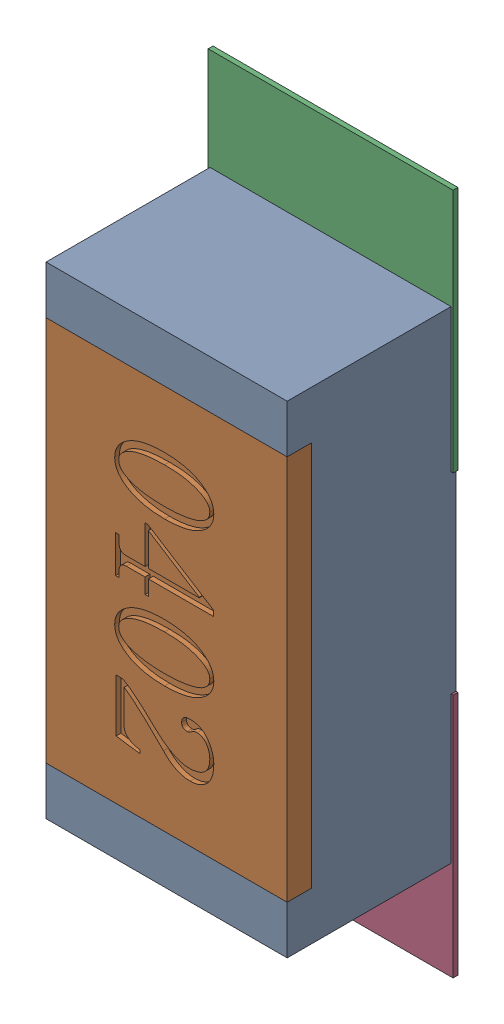
SolidWorks assembly R63, configuration Défaut. Lengths in mm.
Overall size (0.51 1.42 0.35).
5 component instances, 2 part files, 0 mates.
Components (placement in the parent):
- R0402-1: R0402 [Défaut] at (38.4301 -27.1146 0) x (0 -1 0) z (0 0 1) size (1 0.5 0.35)
- 6504207776-1: 6504207776 [Défaut] at (38.4302 -26.6575 0) size (0.51 0.51 0.01)
  - Extruded-1: Extruded [Défaut] at origin size (0.51 0.51 0.01)
- 6504207776-2: 6504207776 [Défaut] at (38.4302 -27.5646 0) size (0.51 0.51 0.01)
  - Extruded-1: Extruded [Défaut] at origin size (0.51 0.51 0.01)
